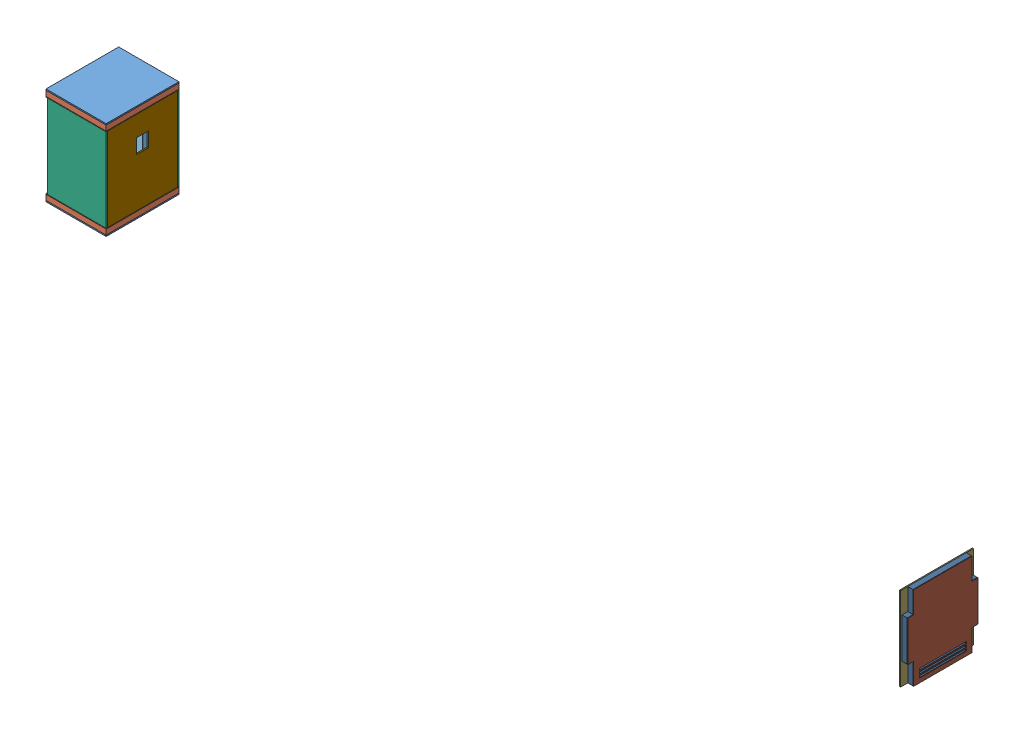
SolidWorks assembly Base_all, configuration Default. Lengths in mm.
Overall size (4119.12 468 348).
25 component instances, 14 part files, 37 mates.
Components (placement in the parent):
- Base_acry-1: Base_acry [Default] at (-21.3696 115.7834 399.5753) size (288 6 348)
- Base_poly-1: Base_poly [Default] at (-21.3696 121.7834 399.5753) size (288 25 348)
- Base-1: Base [Default] at (-21.3696 146.7834 399.5753) size (288 3 348)
- Wide Wall-1: Wide Wall [Default] at (-418.027 603.8939 -47.6319) x (0 0 1) z (1 0 0) size (28 456 276)
  - Wide wall poly-1: Wide wall poly [Default] at (120.1961 235.572 384.7424) size (25 456 276)
  - Wide wall acrylic-2: Wide wall acrylic [Default] at (145.1961 263.572 384.7424) size (3 400 276)
- Wide Wall-2: Wide Wall [Default] at (-418.027 95.6729 528.7602) x (0 0 -1) z (1 0 0) size (28 456 276)
  - Wide wall poly-1: Wide wall poly [Default] at (120.1961 235.572 384.7424) size (25 456 276)
  - Wide wall acrylic-2: Wide wall acrylic [Default] at (145.1961 263.572 384.7424) size (3 400 276)
- Base-2: Base [Default] at (-21.3696 549.7834 399.5753) size (288 3 348)
- Base_poly-2: Base_poly [Default] at (-21.3696 552.7834 399.5753) size (288 25 348)
- Base_acry-2: Base_acry [Default] at (-21.3696 577.7834 399.5753) size (288 6 348)
- Wide wall acrylic full-1: Wide wall acrylic full [Default] at (-27.2846 359.2449 72.5642) x (0 0 -1) z (1 0 0) size (6 400 282)
- Wide wall acrylic full-2: Wide wall acrylic full [Default] at (-27.2846 359.2449 414.5642) x (0 0 -1) z (1 0 0) size (6 400 282)
- Long Wall-2: Long Wall [Default] at (175.3312 372.5607 179.771) x (0 0 -1) z (1 0 0) size (336 456 28)
  - Long wall acrylic-1: Long wall acrylic [Default] at (-119.0139 -10.8946 25.0764) size (336 400 3)
  - Long wall poly-1: Long wall poly [Default] at (-119.0139 -38.8946 28.0764) size (336 456 25)
- Long wall acrylic full-2: Long wall acrylic full [Default] at (228.4077 305.9372 177.7949) x (0 0 -1) z (1 0 0) size (336 400 6)
- Door-1: Door [Default] at (3678.8585 129.7918 320.4669) x (0 0 -1) z (1 0 0) size (348 400 89.5)
  - door wall poly-1: door wall poly [Default] at (21.682 231.8743 358.6656) size (336 400 25)
  - door inner acrylic-1: door inner acrylic [Default] at (21.682 231.8743 383.6656) size (336 400 3)
  - door acrylic outer-1: door acrylic outer [Default] at (136.6719 176.1454 353.6656) size (348 400 5)
  - handle-1: handle [Default] at (171.9027 136.1173 445.2959) size (15 115 86.5)
  - handle-2: handle [Default] at (-12.0973 136.1173 445.2959) size (15 115 86.5)
- peltier holder-1: peltier holder [Default] at (228.4077 368.3794 240.2993) x (-1 0 0) z (0 0 1) size (28 160 80)
Mates (geometry in assembly coordinates):
- Coincident1: coincident: plane of Base_acry-1 through (-53.5923 121.7834 66.5642) normal (-1 0 0); plane of Base_poly-1 through (-53.5923 146.7834 66.5642) normal (-1 0 0)
- Coincident2: coincident: plane of Base_acry-1 through (-53.5923 121.7834 414.5642) normal (0 0 1); plane of Base_poly-1 through (-53.5923 146.7834 414.5642) normal (0 0 1)
- Coincident3: coincident: plane of Base_acry-1 through (-21.3696 121.7834 399.5753) normal (0 1 0); plane of Base_poly-1 through (-21.3696 121.7834 399.5753) normal (0 -1 0)
- Coincident4: coincident: plane of Base_poly-1 through (-53.5923 146.7834 66.5642) normal (-1 0 0); plane of Base-1 through (-53.5923 149.7834 66.5642) normal (-1 0 0)
- Coincident5: coincident: plane of Base_poly-1 through (-53.5923 146.7834 414.5642) normal (0 0 1); plane of Base-1 through (-53.5923 149.7834 414.5642) normal (0 0 1)
- Coincident6: coincident: plane of Base_poly-1 through (-21.3696 146.7834 399.5753) normal (0 1 0); plane of Base-1 through (-21.3696 146.7834 399.5753) normal (0 -1 0)
- Coincident17: coincident: line of Base_poly-1 through (200.4077 121.7834 72.5642) axis (-1 0 0); line of Wide Wall-1/Wide wall poly-1 through (-19.5923 121.7834 72.5642) axis (1 0 0)
- Coincident18: coincident: plane of Base_poly-1 through (200.4077 146.7834 72.5642) normal (-1 0 0); plane of Wide Wall-1/Wide wall poly-1 through (200.4077 149.7834 97.5642) normal (1 0 0)
- Coincident20: coincident: line of Base_poly-1 through (200.4077 121.7834 408.5642) axis (0 0 -1); line of Wide Wall-2/Wide wall poly-1 through (200.4077 121.7834 383.5642) axis (0 0 1)
- Coincident21: coincident: line of Base_poly-1 through (200.4077 121.7834 383.5642) axis (-1 0 0); line of Wide Wall-2/Wide wall poly-1 through (200.4077 121.7834 383.5642) axis (-1 0 0)
- Coincident25: coincident: plane of Wide Wall-1/Wide wall poly-1 through (-19.5923 549.7834 97.5642) normal (-1 0 0); plane of Base-2 through (-19.5923 555.7834 72.5642) normal (1 0 0)
- Coincident26: coincident: plane of Wide Wall-1/Wide wall poly-1 through (-33.2846 368.3219 72.5642) normal (0 0 -1); plane of Base-2 through (-19.5923 555.7834 72.5642) normal (0 0 1)
- Coincident27: coincident: plane of Wide Wall-1/Wide wall poly-1 through (-47.5923 549.7834 97.5642) normal (0 1 0); plane of Base-2 through (-21.3696 549.7834 399.5753) normal (0 -1 0)
- Coincident29: coincident: plane of Base-2 through (-21.3696 552.7834 399.5753) normal (0 1 0); plane of Base_poly-2 through (-21.3696 552.7834 399.5753) normal (0 -1 0)
- Coincident30: coincident: plane of Base-2 through (-53.5923 552.7834 414.5642) normal (0 0 1); plane of Base_poly-2 through (-53.5923 577.7834 414.5642) normal (0 0 1)
- Coincident31: coincident: line of Base_poly-2 through (234.4077 552.7834 414.5642) axis (0 0 -1); line of Base-2 through (234.4077 552.7834 414.5642) axis (0 0 -1)
- Coincident34: coincident: plane of Base_poly-2 through (-21.3696 577.7834 399.5753) normal (0 1 0); plane of Base_acry-2 through (-21.3696 577.7834 399.5753) normal (0 -1 0)
- Coincident35: coincident: plane of Base_poly-2 through (-53.5923 577.7834 414.5642) normal (0 0 1); plane of Base_acry-2 through (-53.5923 583.7834 414.5642) normal (0 0 1)
- Coincident36: coincident: plane of Base_poly-2 through (-53.5923 577.7834 66.5642) normal (-1 0 0); plane of Base_acry-2 through (-53.5923 583.7834 66.5642) normal (-1 0 0)
- Coincident37: coincident: plane of Wide Wall-1/Wide wall poly-1 through (-33.2846 368.3219 72.5642) normal (0 0 -1); plane of Wide wall acrylic full-1 through (-27.2846 359.2449 72.5642) normal (0 0 1)
- Coincident38: coincident: plane of Wide Wall-1/Wide wall poly-1 through (-47.5923 121.7834 97.5642) normal (-1 0 0); plane of Wide wall acrylic full-1 through (-47.5923 549.7834 66.5642) normal (-1 0 0)
- Coincident39: coincident: plane of Base-2 through (-21.3696 549.7834 399.5753) normal (0 -1 0); plane of Wide wall acrylic full-1 through (234.4077 549.7834 66.5642) normal (0 1 0)
- Coincident44: coincident: plane of Wide Wall-2/Wide wall poly-1 through (-33.2846 331.2449 408.5642) normal (0 0 1); plane of Wide wall acrylic full-2 through (-27.2846 359.2449 408.5642) normal (0 0 -1)
- Coincident45: coincident: plane of Wide Wall-2/Wide wall poly-1 through (-47.5923 577.7834 383.5642) normal (-1 0 0); plane of Wide wall acrylic full-2 through (-47.5923 549.7834 408.5642) normal (-1 0 0)
- Coincident46: coincident: plane of Base-2 through (-21.3696 549.7834 399.5753) normal (0 -1 0); plane of Wide wall acrylic full-2 through (234.4077 549.7834 408.5642) normal (0 1 0)
- Coincident47: coincident: line of Wide Wall-1/Wide wall poly-1 through (200.4077 445.7834 72.5642) axis (0 -1 0); line of Long Wall-2/Long wall acrylic-1 through (200.4077 253.7834 72.5642) axis (0 1 0)
- Coincident48: coincident: plane of Wide Wall-1/Wide wall poly-1 through (228.4077 121.7834 97.5642) normal (1 0 0); plane of Long Wall-2/Long wall poly-1 through (228.4077 333.6662 298.7848) normal (1 0 0)
- Coincident49: coincident: plane of Base_acry-2 through (-21.3696 577.7834 399.5753) normal (0 -1 0); plane of Long Wall-2/Long wall poly-1 through (228.4077 577.7834 408.5642) normal (0 1 0)
- Coincident50: coincident: plane of Long Wall-2/Long wall poly-1 through (228.4077 333.6662 298.7848) normal (1 0 0); plane of Long wall acrylic full-2 through (228.4077 305.9372 177.7949) normal (-1 0 0)
- Coincident51: coincident: plane of Base-2 through (-21.3696 549.7834 399.5753) normal (0 -1 0); plane of Long wall acrylic full-2 through (234.4077 549.7834 408.5642) normal (0 1 0)
- Coincident52: coincident: plane of Wide wall acrylic full-1 through (-27.2846 359.2449 72.5642) normal (0 0 1); plane of Long wall acrylic full-2 through (234.4077 549.7834 72.5642) normal (0 0 -1)
- Parallel2: parallel: plane of Wide wall acrylic full-2 through (-27.2846 359.2449 408.5642) normal (0 0 -1); plane of Door-1/door acrylic outer-1 through (4037.5241 549.7834 414.5642) normal (0 0 1)
- Coincident61: coincident: plane of Base-2 through (-21.3696 549.7834 399.5753) normal (0 -1 0); plane of Door-1/door wall poly-1 through (4062.5241 549.7834 408.5642) normal (0 1 0)
- Coincident63: coincident: plane of Wide wall acrylic full-2 through (-27.2846 359.2449 414.5642) normal (0 0 1); plane of Door-1/door acrylic outer-1 through (4037.5241 549.7834 414.5642) normal (0 0 1)
- Coincident66: coincident: plane of Long Wall-2/Long wall poly-1 through (203.4077 497.7834 280.5642) normal (0 -1 0); plane of peltier holder-1 through (200.4077 497.7834 280.5642) normal (0 1 0)
- Coincident67: coincident: plane of Long Wall-2/Long wall poly-1 through (203.4077 497.7834 200.5642) normal (0 0 1); plane of peltier holder-1 through (200.4077 337.7834 200.5642) normal (0 0 -1)
- Coincident68: coincident: plane of Long wall acrylic full-2 through (228.4077 305.9372 177.7949) normal (-1 0 0); plane of peltier holder-1 through (228.4077 368.3794 240.2993) normal (1 0 0)
